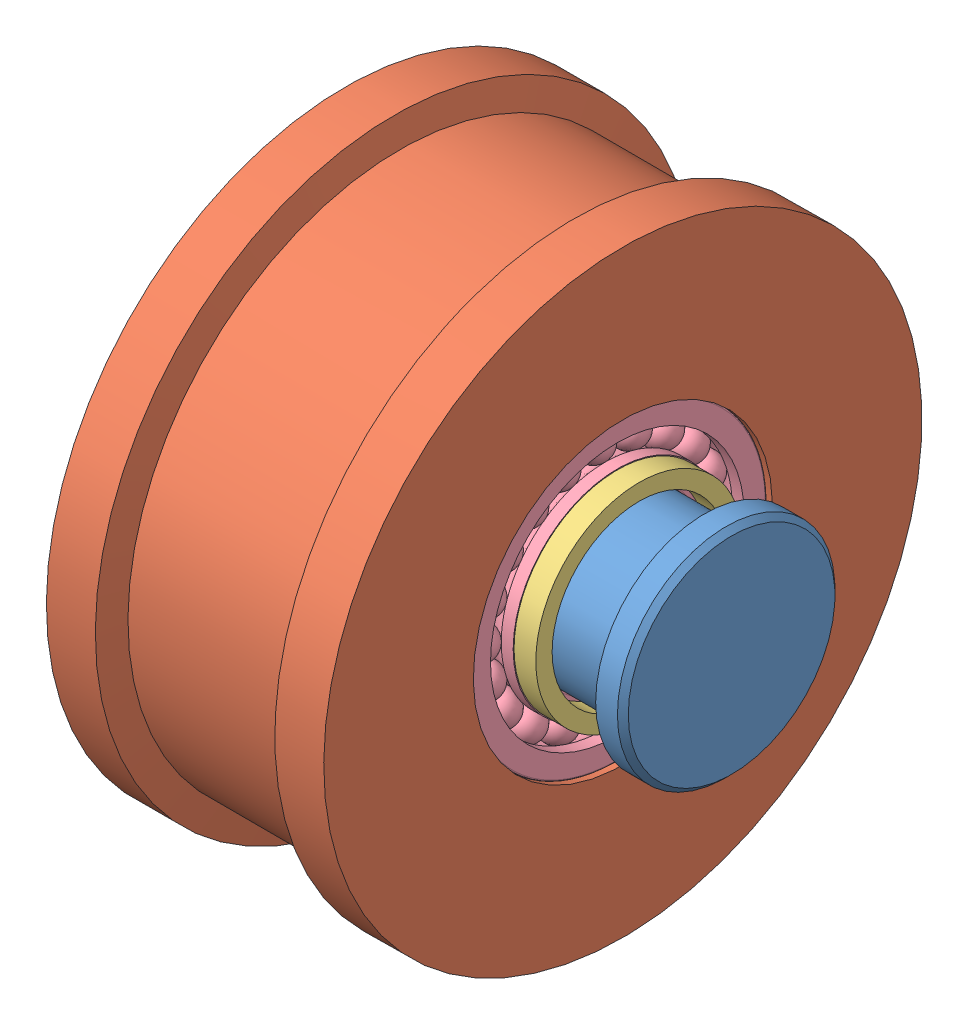
SolidWorks assembly 中臂走轮装配1, configuration 默认. Lengths in mm.
Overall size (92 143.67 143.67).
7 component instances, 5 part files, 13 mates.
Components (placement in the parent):
- 中壁轮轴-1: 中壁轮轴 [默认] at (-46.4527 460.8329 -42.4681) size (87 40 40)
- 中臂走轮-1: 中臂走轮 [默认] at (20.5473 460.8329 -42.4681) x (-1 0 0) z (0 -0.924225 -0.381849) size (51 110 110)
- 中臂走轮挡圈-1: 中臂走轮挡圈 [默认] at (-4182.3659 1373.3903 -4998.0815) size (4 38 38)
- 中臂走轮挡圈-2: 中臂走轮挡圈 [默认] at (-4129.3659 1373.3903 -4998.0815) size (4 38 38)
- deep groove ball bearings gb-1: deep groove ball bearings gb [Rolling bearings 16006 GB 276-94] at (15.0473 460.8329 -42.4681) size (9 55 55)
- deep groove ball bearings gb-2: deep groove ball bearings gb [Rolling bearings 16006 GB 276-94] at (-24.9527 460.8329 -42.4681) size (9 55 55)
- GB T892 B30挡圈-1: GB T892 B30挡圈 [默认] at (-46.4527 460.8329 -42.4681) x (-1 0 0) z (0 -0.924225 -0.381849) size (5 45 45)
Mates (geometry in assembly coordinates):
- 同心8: concentric: cylinder of 中臂走轮-1 through (-30.4527 460.8329 -42.4681) axis (-1 0 0) radius 27.5; cylinder of deep groove ball bearings gb-2 through (-33.6633 460.8329 -42.4681) axis (-1 0 0) radius 27.5
- 重合1: coincident: circle of 中臂走轮-1; plane of deep groove ball bearings gb-2 through (-20.4527 488.3329 -42.4681) normal (1 0 0)
- 同心3: concentric: cylinder of 中臂走轮-1 through (-30.4527 460.8329 -42.4681) axis (-1 0 0) radius 27.5; cylinder of deep groove ball bearings gb-1 through (6.3367 460.8329 -42.4681) axis (-1 0 0) radius 27.5
- 重合2: coincident: plane of 中臂走轮-1 through (10.5473 438.1894 -51.8234) normal (1 0 0); plane of deep groove ball bearings gb-1 through (10.5473 488.3329 -42.4681) normal (-1 0 0)
- 同心4: concentric: cylinder of 中臂走轮-1 through (-30.4527 460.8329 -42.4681) axis (-1 0 0) radius 27.5; cylinder of 中臂走轮挡圈-2 through (2.5473 460.8329 -42.4681) axis (-1 0 0) radius 19
- 重合3: coincident: plane of 中臂走轮挡圈-2 through (19.5473 460.7807 -58.468) normal (-1 0 0); plane of deep groove ball bearings gb-1 through (19.5473 475.8329 -42.4681) normal (1 0 0)
- 同心5: concentric: cylinder of 中臂走轮-1 through (-30.4527 460.8329 -42.4681) axis (-1 0 0) radius 27.5; cylinder of 中臂走轮挡圈-1 through (-50.4527 460.8329 -42.4681) axis (-1 0 0) radius 19
- 重合4: coincident: plane of 中臂走轮挡圈-1 through (-29.4527 460.7807 -58.468) normal (1 0 0); plane of deep groove ball bearings gb-2 through (-29.4527 479.9996 -42.4681) normal (-1 0 0)
- 同心6: concentric: cylinder of 中壁轮轴-1 through (35.5473 460.8329 -42.4681) axis (-1 0 0) radius 15; cylinder of deep groove ball bearings gb-2 through (-31.9241 460.8329 -42.4681) axis (-1 0 0) radius 15
- 距离1: distance = 12 mm: plane of 中臂走轮挡圈-2 through (23.5473 460.7807 -58.468) normal (1 0 0); plane of 中壁轮轴-1 through (35.5473 460.8329 -42.4681) normal (-1 0 0)
- 同心9: concentric: cylinder of 中壁轮轴-1 through (35.5473 460.8329 -42.4681) axis (-1 0 0) radius 15; cylinder of deep groove ball bearings gb-2 through (-31.9241 460.8329 -42.4681) axis (-1 0 0) radius 15
- 重合6: coincident: plane of 中壁轮轴-1 through (-46.4527 460.8329 -42.4681) normal (-1 0 0); plane of GB T892 B30挡圈-1 through (-46.4527 460.8329 -42.4681) normal (1 0 0)
- 同心10: concentric: cylinder of 中壁轮轴-1 through (-46.4527 460.8329 -42.4681) axis (-1 0 0) radius 3.4; cylinder of GB T892 B30挡圈-1 through (-51.4527 460.8329 -42.4681) axis (1 0 0) radius 3.3
